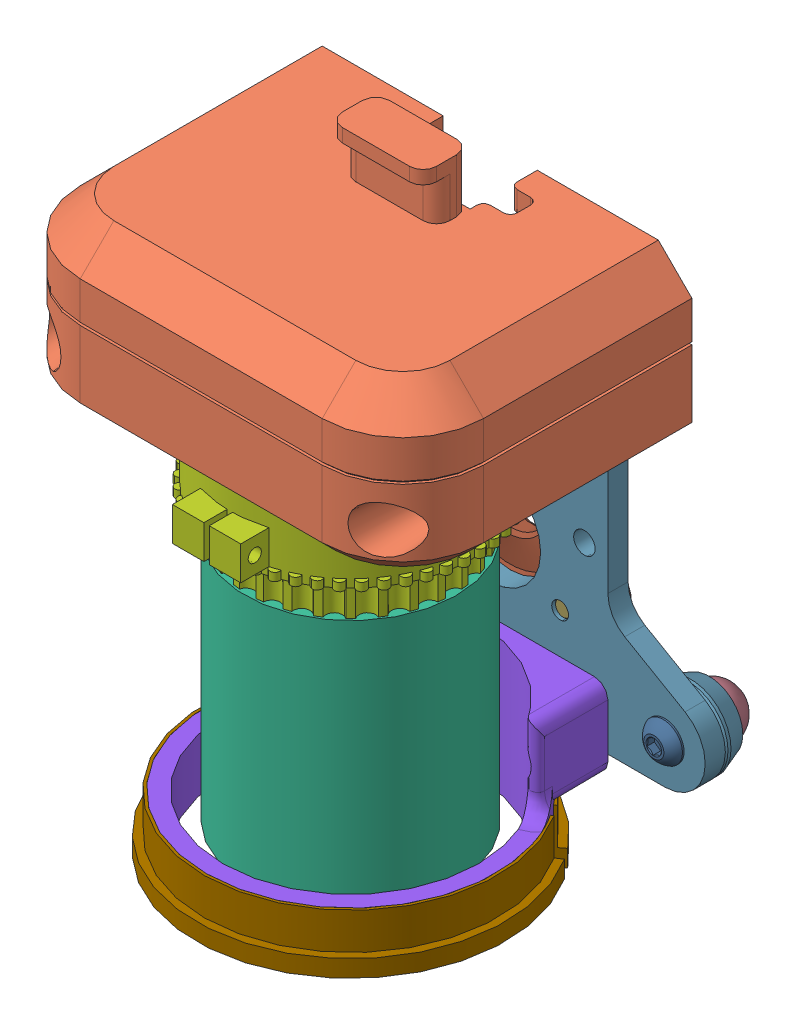
SolidWorks assembly webcam_mockup, configuration Default. Lengths in mm.
Overall size (102.25 185.08 104.82).
40 component instances, 14 part files, 54 mates.
Components (placement in the parent):
- camera_holder_assembly-1: camera_holder_assembly [Default] at (45.3164 3.249 -5.7693) size (102.25 185.08 88.2)
  - rpi_hq_uvc_adapter_board-1: rpi_hq_uvc_adapter_board [Default] at (20.2172 82.4988 16.7828) x (-1 0 0) z (0 1 0) size (38 38 6.17)
  - printed_base-1: printed_base [Printed Lid] at (20.2172 46.0688 -6.9672) size (102.25 179.33 88.2)
  - m2.5_16mm_socket_cap_screw_91292A018-1: m2.5_16mm_socket_cap_screw_91292A018 [91292A018] at (5.2172 88.2388 1.7828) x (1 0 0) z (0 1 0) size (4.5 4.5 18.7)
  - m2.5_16mm_socket_cap_screw_91292A018-2: m2.5_16mm_socket_cap_screw_91292A018 [91292A018] at (35.2172 88.2388 1.7828) x (1 0 0) z (0 1 0) size (4.5 4.5 18.7)
  - m2.5_16mm_socket_cap_screw_91292A018-3: m2.5_16mm_socket_cap_screw_91292A018 [91292A018] at (35.2172 88.2388 31.7828) x (1 0 0) z (0 1 0) size (4.5 4.5 18.7)
  - m2.5_16mm_socket_cap_screw_91292A018-4: m2.5_16mm_socket_cap_screw_91292A018 [91292A018] at (5.2172 88.2388 31.7828) x (1 0 0) z (0 1 0) size (4.5 4.5 18.7)
  - printed_base_assembly-1: printed_base_assembly [Default] at (-1.6813 0 1.4527) size (102.25 179.33 88.2)
    - printed_base-1: printed_base [Printed Lower Base] at (21.8985 46.0688 -8.4198) size (102.25 179.33 88.2)
    - m3_heat_set_insert_94180A331-1: m3_heat_set_insert_94180A331 [94180A331] at (7.8985 78.5688 -5.4198) x (0.928039 0.372484 0) z (-0.372484 0.928039 0) size (5.56 4.12 5.56)
    - m3_heat_set_insert_94180A331-2: m3_heat_set_insert_94180A331 [94180A331] at (35.8985 78.5688 -5.4198) x (0.997541 -0.070079 0) z (0.070079 0.997541 0) size (5.56 4.12 5.56)
    - 5x9x2_oring-1: 5x9x2_oring [Default] at (3.6485 78.0688 10.3302) x (0.994492 0 -0.104809) z (0.104809 0 0.994492) size (9 3.15 9)
    - 5x9x2_oring-2: 5x9x2_oring [Default] at (40.1485 78.0688 10.3302) x (-0.984669 0 0.174435) z (-0.174435 0 -0.984669) size (9 3.15 9)
  - sensor_with_lens-1: sensor_with_lens [Default] at origin size (41.64 98.45 42.27)
    - lens_mockup-1: lens_mockup [Default] at (20.2172 18.1388 16.7828) x (0.912257 0 0.409619) z (-0.409619 0 0.912257) size (31.5 38.9 31.5)
    - rasperry_pi_hq_camera-1: rasperry_pi_hq_camera [No Base Mount] at (1.2172 73.6388 35.7828) x (1 0 0) z (0 0 -1) size (38 98.45 41.45)
- cob_mount_assembly-1: cob_mount_assembly [Default] at (45.3164 3.249 -5.7693) size (64.54 20 64.54)
  - cob_led_mount-1: cob_led_mount [Default] at (20.2172 14.0688 16.7828) size (43 20 43)
  - m3_heat_set_insert_94180A331-1: m3_heat_set_insert_94180A331 [94180A331] at (6.2172 28.0688 -3.9672) x (0.928039 0.372484 0) z (-0.372484 0.928039 0) size (5.56 4.12 5.56)
  - m3_heat_set_insert_94180A331-2: m3_heat_set_insert_94180A331 [94180A331] at (34.2172 28.0688 -3.9672) x (0.722417 0.691458 0) z (-0.691458 0.722417 0) size (5.56 4.12 5.56)
  - cob_led_strip_cut-1: cob_led_strip_cut [Default] at (20.2172 14.0688 16.7828) x (0.790517 0 -0.61244) z (0.61244 0 0.790517) size (46 8 46)
- base_tool_plate_assembly-1: base_tool_plate_assembly [Default] at (42.1833 -40.5603 -164.2195) size (63.96 179.33 108.67)
  - m3_6mm_buttonhead_screw_92095A179-1: m3_6mm_buttonhead_screw_92095A179 [92095A179] at (49.3311 74.8782 156.133) x (-0.992968 0.118386 0) z (0 0 1) size (5.7 5.7 7.94)
  - wedge_plate-1: wedge_plate [Default] at (23.3504 89.8782 151.483) x (-1 0 0) z (0 0 1) size (28.78 26 5.61)
  - m3_6mm_flathead_screw_92125A126-1: m3_6mm_flathead_screw_92125A126 [92125A126] at (33.7427 83.8782 148.033) x (0.923728 0.383049 0) z (0 0 -1) size (6 6 6.28)
  - m3_6mm_flathead_screw_92125A126-2: m3_6mm_flathead_screw_92125A126 [92125A126] at (23.3504 101.8782 148.033) x (0.923728 0.383049 0) z (0 0 -1) size (6 6 6.28)
  - m3_6mm_flathead_screw_92125A126-3: m3_6mm_flathead_screw_92125A126 [92125A126] at (12.9581 83.8782 148.033) x (0.923728 0.383049 0) z (0 0 -1) size (6 6 6.28)
  - m3_threaded_ball-1: m3_threaded_ball [Default] at (1.28 74.0361 147.583) x (-0.210511 -0.977591 0) z (0 0 -1) size (8 8 7.78)
  - metal_base_tool_plate-1: metal_base_tool_plate [Tool Plate] at (23.3504 89.8782 151.483) size (63.96 179.33 88.2)
  - m3_threaded_ball-2: m3_threaded_ball [Default] at (51.3747 71.4396 147.583) x (-0.85964 -0.5109 0) z (0 0 -1) size (8 8 7.78)
  - m3_threaded_ball-3: m3_threaded_ball [Default] at (27.3352 120.2261 147.583) x (0.08699 -0.996209 0) z (0 0 -1) size (8 8 7.78)
  - m3_6mm_buttonhead_screw_92095A179-2: m3_6mm_buttonhead_screw_92095A179 [92095A179] at (-2.6304 74.8782 156.133) x (-0.992968 0.118386 0) z (0 0 1) size (5.7 5.7 7.94)
  - m3_6mm_buttonhead_screw_92095A179-3: m3_6mm_buttonhead_screw_92095A179 [92095A179] at (23.3504 119.8782 156.133) x (-0.992968 0.118386 0) z (0 0 1) size (5.7 5.7 7.94)
  - metal_base_tool_plate-2: metal_base_tool_plate [Tool Ball Cup] at (23.3504 89.8782 151.483) size (11.98 11.98 3.6)
  - metal_base_tool_plate-3: metal_base_tool_plate [Tool Ball Cup] at (49.3311 44.8782 151.483) size (11.98 11.98 3.6)
  - metal_base_tool_plate-4: metal_base_tool_plate [Tool Ball Cup] at (-2.6304 44.8782 151.483) size (11.98 11.98 3.6)
- m3_6mm_buttonhead_screw_92095A179-4: m3_6mm_buttonhead_screw_92095A179 [92095A179] at (79.5336 81.8179 -14.3865) x (0.923728 0.383049 0) z (0 0 -1) size (5.7 5.7 7.94)
- m3_6mm_buttonhead_screw_92095A179-5: m3_6mm_buttonhead_screw_92095A179 [92095A179] at (51.5336 81.8179 -14.3865) x (0.923728 0.383049 0) z (0 0 -1) size (5.7 5.7 7.94)
- m3_6mm_buttonhead_screw_92095A179-6: m3_6mm_buttonhead_screw_92095A179 [92095A179] at (51.5336 31.3179 -14.3865) x (0.923728 0.383049 0) z (0 0 -1) size (5.7 5.7 7.94)
- m3_6mm_buttonhead_screw_92095A179-7: m3_6mm_buttonhead_screw_92095A179 [92095A179] at (79.5336 31.3179 -14.3865) x (0.923728 0.383049 0) z (0 0 -1) size (5.7 5.7 7.94)
Mates (geometry in assembly coordinates):
- Parallel1: parallel aligned: plane of raspberrpy_pi_zero_w-1 through (48.1368 43.0781 20.3109) normal (1 0 0); plane of base_tool_plate_trimmed-1 through (19.3372 29.5489 7.3432) normal (0 0 1)
- Parallel2: parallel anti-aligned: plane of raspberrpy_pi_zero_w-1 through (62.4006 58.2488 26.7029) normal (-1 0 0); plane of rpi_hq_base_tool_plate-1 through (37.7172 82.0688 -3.9672) normal (1 0 0)
- Concentric1: concentric aligned: cylinder of rpi_hq_base_tool_plate-1 through (46.198 31.0688 -3.9672) axis (0 0 1) radius 1.6; cylinder of m3_threaded_ball-1 through (46.198 31.0688 -6.8672) axis (0 0 1) radius 1.25
- Concentric2: concentric: sphere of rpi_hq_base_tool_plate-1; sphere of m3_threaded_ball-1
- Concentric3: concentric aligned: cylinder of rpi_hq_base_tool_plate-1 through (-5.7636 31.0688 -3.9672) axis (0 0 1) radius 1.6; cylinder of m3_threaded_ball-2 through (-5.7636 31.0688 -6.8672) axis (0 0 1) radius 1.25
- Concentric4: concentric: sphere of rpi_hq_base_tool_plate-1; sphere of m3_threaded_ball-2
- Concentric5: concentric aligned: cylinder of rpi_hq_base_tool_plate-1 through (20.2172 76.0688 -3.9672) axis (0 0 1) radius 1.6; cylinder of m3_threaded_ball-3 through (20.2172 76.0688 -6.8672) axis (0 0 1) radius 1.25
- Concentric6: concentric: sphere of rpi_hq_base_tool_plate-1; sphere of m3_threaded_ball-3
- Concentric71: concentric aligned: cylinder of rpi_hq_base_tool_plate-1 through (46.198 31.0688 -3.9672) axis (0 0 1) radius 1.6; cylinder of m3_6mm_buttonhead_screw_92095A179-1 through (46.198 31.0688 -2.3172) axis (0 0 1) radius 2.85
- Coincident31: coincident anti-aligned: plane of rpi_hq_base_tool_plate-1 through (46.198 31.0688 -3.9672) normal (0 0 1); plane of m3_6mm_buttonhead_screw_92095A179-1 through (46.198 28.2188 -3.9672) normal (0 0 -1)
- Concentric81: concentric aligned: cylinder of rpi_hq_base_tool_plate-1 through (-5.7636 31.0688 -3.9672) axis (0 0 1) radius 1.6; cylinder of m3_6mm_buttonhead_screw_92095A179-2 through (-5.7636 31.0688 -2.3172) axis (0 0 1) radius 2.85
- Coincident41: coincident anti-aligned: plane of rpi_hq_base_tool_plate-1 through (46.198 31.0688 -3.9672) normal (0 0 1); plane of m3_6mm_buttonhead_screw_92095A179-2 through (-5.7636 28.2188 -3.9672) normal (0 0 -1)
- Concentric91: concentric aligned: cylinder of rpi_hq_base_tool_plate-1 through (20.2172 76.0688 -3.9672) axis (0 0 1) radius 1.6; cylinder of m3_6mm_buttonhead_screw_92095A179-3 through (20.2172 76.0688 -2.3172) axis (0 0 1) radius 2.85
- Coincident51: coincident anti-aligned: plane of rpi_hq_base_tool_plate-1 through (46.198 31.0688 -3.9672) normal (0 0 1); plane of m3_6mm_buttonhead_screw_92095A179-3 through (20.2172 73.2188 -3.9672) normal (0 0 -1)
- Parallel5: parallel: plane of rpi_hq_base_tool_plate-1 through (46.198 31.0688 -6.9672) normal (0 0 -1); plane of raspberrpy_pi_zero_w-3 through (48.9672 54.185 -60.314) normal (0 0 -1)
- Parallel6: parallel: plane of rpi_hq_base_tool_plate-1 through (2.7172 82.0688 -3.9672) normal (-1 0 0); plane of raspberrpy_pi_zero_w-3 through (-12.2828 54.185 -34.064) normal (-1 0 0)
- Width2: width: plane of raspberrpy_pi_zero_w-3 through (-12.2828 54.185 -34.064) normal (-1 0 0); plane of rpi_hq_base_tool_plate-1 through (52.7172 54.185 -34.064) normal (1 0 0); plane of raspberrpy_pi_zero_w-3 through (2.7172 82.0688 -3.9672) normal (-1 0 0); plane of rpi_hq_base_tool_plate-1 through (37.7172 82.0688 -3.9672) normal (1 0 0)
- Parallel7: parallel aligned: plane of rpi_hq_base_tool_plate-1 through (46.198 31.0688 -3.9672) normal (0 0 1); plane of raspberrpy_pi_zero_w-4 through (42.7984 85.1663 31.3548) normal (0 0 1)
- Parallel8: parallel aligned: plane of rpi_hq_base_tool_plate-1 through (2.7172 82.0688 -3.9672) normal (-1 0 0); plane of raspberrpy_pi_zero_w-4 through (-18.4516 85.1663 27.6048) normal (-1 0 0)
- Parallel9: parallel anti-aligned: plane of rpi_hq_base_tool_plate-1 through (37.7172 82.0688 -3.9672) normal (1 0 0); plane of raspberrpy_pi_zero_w-5 through (42.7172 23.8052 29.8478) normal (-1 0 0)
- Parallel10: parallel aligned: plane of rpi_hq_base_tool_plate-1 through (46.198 31.0688 -3.9672) normal (0 0 1); plane of raspberrpy_pi_zero_w-5 through (44.2172 23.8052 33.5978) normal (0 0 1)
- Concentric96: concentric anti-aligned: cylinder of rpi_hq_base_tool_plate-1 through (6.2172 78.5688 -3.9672) axis (0 0 1) radius 1.25; cylinder of sensor_mount-1 through (6.2172 78.5688 1.0328) axis (0 0 -1) radius 2.55
- Coincident54: coincident anti-aligned: plane of sensor_mount-1 through (42.7172 74.8688 34.0328) normal (1 0 0); plane of raspberrpy_pi_zero_w-5 through (42.7172 23.8052 29.8478) normal (-1 0 0)
- Coincident55: coincident anti-aligned: plane of rpi_hq_base_tool_plate-1 through (46.198 31.0688 -3.9672) normal (0 0 1); plane of sensor_mount-1 through (42.7172 74.8688 -3.9672) normal (0 0 -1)
- Concentric110: concentric aligned: cylinder of rpi_hq_base_tool_plate-1 through (20.2172 58.0688 -6.9672) axis (0 0 -1) radius 1.25; cylinder of wedge_plate-1 through (20.2172 58.0688 -10.5672) axis (0 0 -1) radius 1.6
- Concentric111: concentric aligned: cylinder of rpi_hq_base_tool_plate-1 through (30.6095 40.0688 -6.9672) axis (0 0 -1) radius 1.25; cylinder of wedge_plate-1 through (30.6095 40.0688 -10.5672) axis (0 0 -1) radius 1.6
- Coincident69: coincident anti-aligned: plane of rpi_hq_base_tool_plate-1 through (46.198 31.0688 -6.9672) normal (0 0 -1); plane of wedge_plate-1 through (20.2172 46.0688 -6.9672) normal (0 0 1)
- Coincident701: coincident aligned: cone of wedge_plate-1 through (30.6095 40.0688 -10.5672) axis (0 0 1); cone of m3_6mm_flathead_screw_92125A126-1 through (30.6095 40.0688 -8.7172) axis (0 0 1)
- Coincident711: coincident aligned: cone of wedge_plate-1 through (20.2172 58.0688 -10.5672) axis (0 0 1); cone of m3_6mm_flathead_screw_92125A126-2 through (20.2172 58.0688 -8.7172) axis (0 0 1)
- Coincident721: coincident aligned: cone of wedge_plate-1 through (9.8249 40.0688 -10.5672) axis (0 0 1); cone of m3_6mm_flathead_screw_92125A126-3 through (9.8249 40.0688 -8.7172) axis (0 0 1)
- Coincident729: coincident anti-aligned: plane of rpi_hq_base_tool_plate-1 through (46.198 31.0688 -3.9672) normal (0 0 1); plane of cob_mount_assembly-1/cob_led_mount-1 through (83.0336 37.3179 -9.7365) normal (0 0 -1)
- Width14: width anti-aligned: plane of cob_mount_assembly-1/cob_led_mount-1 through (83.0336 37.3179 -9.7365) normal (1 0 0); plane of cob_mount_assembly-1/cob_led_mount-1 through (48.0336 37.3179 -9.7365) normal (-1 0 0); plane of rpi_hq_base_tool_plate-1 through (2.7172 82.0688 -3.9672) normal (-1 0 0); plane of rpi_hq_base_tool_plate-1 through (37.7172 82.0688 -3.9672) normal (1 0 0)
- Concentric1084: concentric anti-aligned: cylinder of rpi_hq_base_tool_plate-1 through (34.2172 28.0688 -3.9672) axis (0 0 1) radius 1.25; cylinder of cob_mount_assembly-1/cob_led_mount-1 through (79.5336 31.3179 32.5135) axis (0 0 -1) radius 2.55
- Concentric1091: concentric anti-aligned: cylinder of rpi_hq_base_tool_plate-1 through (34.2172 78.5688 -3.9672) axis (0 0 1) radius 1.25; cylinder of camera_holder_assembly-1/printed_base_assembly-1/printed_base-1 through (79.5336 81.8179 -5.7365) axis (0 0 -1) radius 2.55
- Concentric1092: concentric anti-aligned: cylinder of rpi_hq_base_tool_plate-1 through (6.2172 78.5688 -3.9672) axis (0 0 1) radius 1.25; cylinder of camera_holder_assembly-1/printed_base_assembly-1/printed_base-1 through (51.5336 81.8179 -5.7365) axis (0 0 -1) radius 2.55
- Coincident736: coincident anti-aligned: plane of rpi_hq_base_tool_plate-1 through (46.198 31.0688 -3.9672) normal (0 0 1); plane of camera_holder_assembly-1/printed_base_assembly-1/printed_base-1 through (35.5336 75.3179 -9.7365) normal (0 0 -1)
- Width20: width anti-aligned: plane of camera_holder_assembly-1/sensor_with_lens-1/rasperry_pi_hq_camera-1 through (46.5336 76.8879 27.5135) normal (-1 0 0); plane of rpi_hq_base_tool_plate-1 through (84.5336 76.8879 -5.4865) normal (1 0 0); plane of camera_holder_assembly-1/sensor_with_lens-1/rasperry_pi_hq_camera-1 through (37.7172 82.0688 -3.9672) normal (1 0 0); plane of rpi_hq_base_tool_plate-1 through (2.7172 82.0688 -3.9672) normal (-1 0 0)
- Concentric1093: concentric: cylinder of camera_holder_assembly-1/sensor_with_lens-1/rasperry_pi_hq_camera-1 through (65.5336 65.2879 11.0135) axis (0 -1 0) radius 18; cylinder of ? through (20.2172 74.8688 15.0328) axis (0 1 0) radius 18
- Concentric1094: concentric: cylinder of camera_holder_assembly-1/sensor_with_lens-1/rasperry_pi_hq_camera-1 through (50.5336 76.8879 -3.9865) axis (0 -1 0) radius 1.25; cylinder of ? through (5.2172 81.5688 0.0328) axis (0 1 0) radius 1.5
- Coincident737: coincident: plane of camera_holder_assembly-1/sensor_with_lens-1/rasperry_pi_hq_camera-1 through (65.5336 75.4879 11.0135) normal (0 -1 0); plane of ? through (39.2172 85.0688 34.0328) normal (0 1 0)
- Width21: width aligned: plane of camera_holder_assembly-1/printed_base_assembly-1/printed_base-1 through (95.5336 75.3179 33.2635) normal (1 0 0); plane of camera_holder_assembly-1/printed_base_assembly-1/printed_base-1 through (35.5336 75.3179 33.2635) normal (-1 0 0); plane of base_tool_plate_assembly-1/metal_base_tool_plate-1 through (83.0336 85.3179 -9.7365) normal (1 0 0); plane of base_tool_plate_assembly-1/metal_base_tool_plate-1 through (48.0336 85.3179 -9.7365) normal (-1 0 0)
- Concentric1095: concentric anti-aligned: circle of camera_holder_assembly-1/printed_base_assembly-1/m3_heat_set_insert_94180A331-1; cylinder of base_tool_plate_assembly-1/metal_base_tool_plate-1 through (51.5336 81.8179 -9.7365) axis (0 0 1) radius 1.6
- Coincident738: coincident anti-aligned: plane of camera_holder_assembly-1/printed_base_assembly-1/printed_base-1 through (35.5336 75.3179 -9.7365) normal (0 0 -1); plane of base_tool_plate_assembly-1/metal_base_tool_plate-1 through (91.5144 34.3179 -9.7365) normal (0 0 1)
- Width22: width aligned: plane of cob_mount_assembly-1/cob_led_mount-1 through (48.0336 37.3179 -9.7365) normal (-1 0 0); plane of cob_mount_assembly-1/cob_led_mount-1 through (83.0336 37.3179 -9.7365) normal (1 0 0); plane of base_tool_plate_assembly-1/metal_base_tool_plate-1 through (48.0336 85.3179 -9.7365) normal (-1 0 0); plane of base_tool_plate_assembly-1/metal_base_tool_plate-1 through (83.0336 85.3179 -9.7365) normal (1 0 0)
- Concentric1096: concentric aligned: circle of cob_mount_assembly-1/cob_led_mount-1; cylinder of base_tool_plate_assembly-1/metal_base_tool_plate-1 through (79.5336 31.3179 -9.7365) axis (0 0 1) radius 1.6
- Coincident739: coincident anti-aligned: plane of cob_mount_assembly-1/cob_led_mount-1 through (83.0336 37.3179 -9.7365) normal (0 0 -1); plane of base_tool_plate_assembly-1/metal_base_tool_plate-1 through (91.5144 34.3179 -9.7365) normal (0 0 1)
- Concentric10971: concentric anti-aligned: cylinder of base_tool_plate_assembly-1/metal_base_tool_plate-1 through (79.5336 81.8179 -9.7365) axis (0 0 1) radius 1.6; cylinder of m3_6mm_buttonhead_screw_92095A179-4 through (79.5336 81.8179 -14.3865) axis (0 0 -1) radius 2.85
- Coincident7401: coincident anti-aligned: plane of base_tool_plate_assembly-1/metal_base_tool_plate-1 through (91.5144 34.3179 -12.7365) normal (0 0 -1); plane of m3_6mm_buttonhead_screw_92095A179-4 through (78.442 84.4505 -12.7365) normal (0 0 1)
- Concentric10981: concentric anti-aligned: cylinder of base_tool_plate_assembly-1/metal_base_tool_plate-1 through (51.5336 81.8179 -9.7365) axis (0 0 1) radius 1.6; cylinder of m3_6mm_buttonhead_screw_92095A179-5 through (51.5336 81.8179 -14.3865) axis (0 0 -1) radius 2.85
- Coincident7411: coincident anti-aligned: plane of base_tool_plate_assembly-1/metal_base_tool_plate-1 through (91.5144 34.3179 -12.7365) normal (0 0 -1); plane of m3_6mm_buttonhead_screw_92095A179-5 through (50.442 84.4505 -12.7365) normal (0 0 1)
- Concentric10991: concentric anti-aligned: cylinder of base_tool_plate_assembly-1/metal_base_tool_plate-1 through (51.5336 31.3179 -9.7365) axis (0 0 1) radius 1.6; cylinder of m3_6mm_buttonhead_screw_92095A179-6 through (51.5336 31.3179 -14.3865) axis (0 0 -1) radius 2.85
- Coincident7421: coincident anti-aligned: plane of base_tool_plate_assembly-1/metal_base_tool_plate-1 through (91.5144 34.3179 -12.7365) normal (0 0 -1); plane of m3_6mm_buttonhead_screw_92095A179-6 through (50.442 33.9505 -12.7365) normal (0 0 1)
- Concentric11001: concentric anti-aligned: cylinder of base_tool_plate_assembly-1/metal_base_tool_plate-1 through (79.5336 31.3179 -9.7365) axis (0 0 1) radius 1.6; cylinder of m3_6mm_buttonhead_screw_92095A179-7 through (79.5336 31.3179 -14.3865) axis (0 0 -1) radius 2.85
- Coincident7431: coincident anti-aligned: plane of base_tool_plate_assembly-1/metal_base_tool_plate-1 through (91.5144 34.3179 -12.7365) normal (0 0 -1); plane of m3_6mm_buttonhead_screw_92095A179-7 through (78.442 33.9505 -12.7365) normal (0 0 1)
